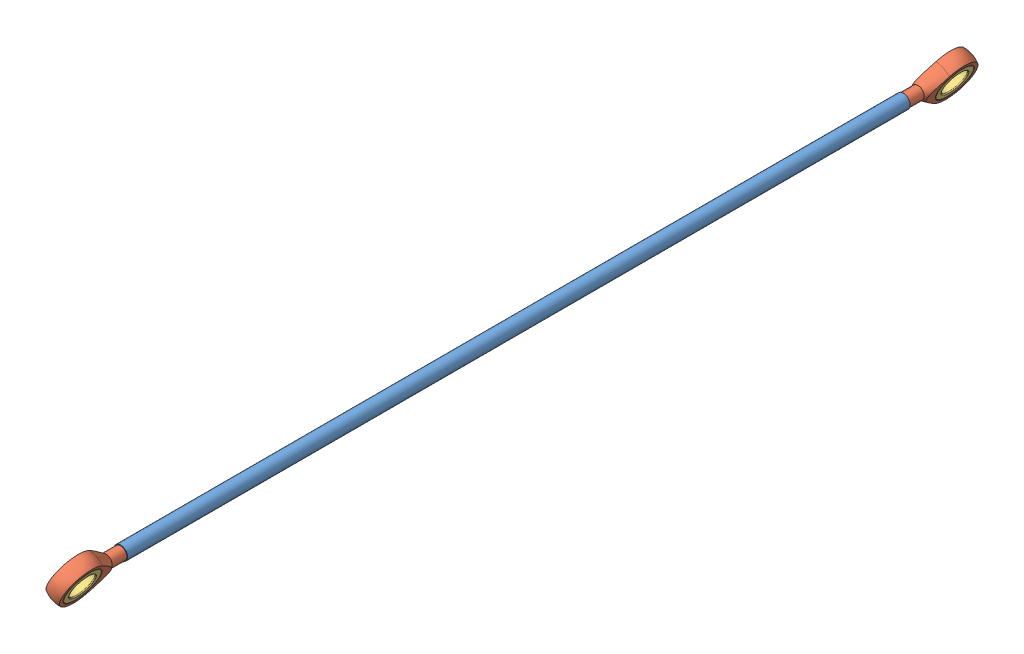
SolidWorks assembly SubTayDuoi, configuration Default. Lengths in mm.
Overall size (13.19 18.82 368).
5 component instances, 3 part files, 9 mates.
Components (placement in the parent):
- TayDuoi-1: TayDuoi [Default] at origin size (5.5 5.5 314)
- Male Rod End Bearing HS-1: Male Rod End Bearing HS [Default] at (0 0 -18) x (0.432471 0.901648 0) z (0 0 1) size (18 6 42)
- Male Rod End Bearing HS-2: Male Rod End Bearing HS [Default] at (0 0 332) x (-0.432471 -0.901648 0) z (0 0 -1) size (18 6 42)
- Ball Washer HS-1: Ball Washer HS [Default] at (0 0 332) x (0.432471 0.901648 0) z (0 0 1) size (14.4 6 14.4)
- Ball Washer HS-2: Ball Washer HS [Default] at (0 0 -18) x (0.432471 0.901648 0) z (0 0 1) size (14.4 6 14.4)
Mates (geometry in assembly coordinates):
- Distance1: distance = 18 mm: plane of TayDuoi-1 through (0 0 0) normal (0 0 -1); point of Male Rod End Bearing HS-1
- Concentric1: concentric anti-aligned: cylinder of TayDuoi-1 through (0 0 314) axis (0 0 -1) radius 2.5; cylinder of Male Rod End Bearing HS-1 through (0 0 -27.001) axis (0 0 1) radius 2.5
- Concentric2: concentric aligned: cylinder of TayDuoi-1 through (0 0 314) axis (0 0 -1) radius 2.5; cylinder of Male Rod End Bearing HS-2 through (0 0 341.001) axis (0 0 -1) radius 2.5
- Distance2: distance = 18 mm: plane of TayDuoi-1 through (0 0 314) normal (0 0 1)
- Coincident3: coincident aligned: plane of Male Rod End Bearing HS-1 through (-6.3746 -6.3533 -18) normal (-0.901648 0.432471 0); plane of Male Rod End Bearing HS-2 through (0.9647 8.9481 332) normal (-0.901648 0.432471 0)
- Concentric3: concentric aligned: cylinder of Male Rod End Bearing HS-2 through (3.9562 -1.8976 332) axis (0.901648 -0.432471 0) radius 7.2; cylinder of Ball Washer HS-1 through (3.4351 -1.6476 332) axis (0.901648 -0.432471 0) radius 7.2
- Coincident4: coincident aligned: plane of Male Rod End Bearing HS-2 through (0.9647 8.9481 332) normal (-0.901648 0.432471 0); plane of Ball Washer HS-1 through (-4.7269 -2.918 332) normal (-0.901648 0.432471 0)
- Concentric4: concentric aligned: cylinder of Male Rod End Bearing HS-1 through (3.9562 -1.8976 -18) axis (0.901648 -0.432471 0) radius 7.2; cylinder of Ball Washer HS-2 through (3.4351 -1.6476 -18) axis (0.901648 -0.432471 0) radius 7.2
- Coincident5: coincident aligned: plane of Male Rod End Bearing HS-1 through (-6.3746 -6.3533 -18) normal (-0.901648 0.432471 0); plane of Ball Washer HS-2 through (-4.7269 -2.918 -18) normal (-0.901648 0.432471 0)
